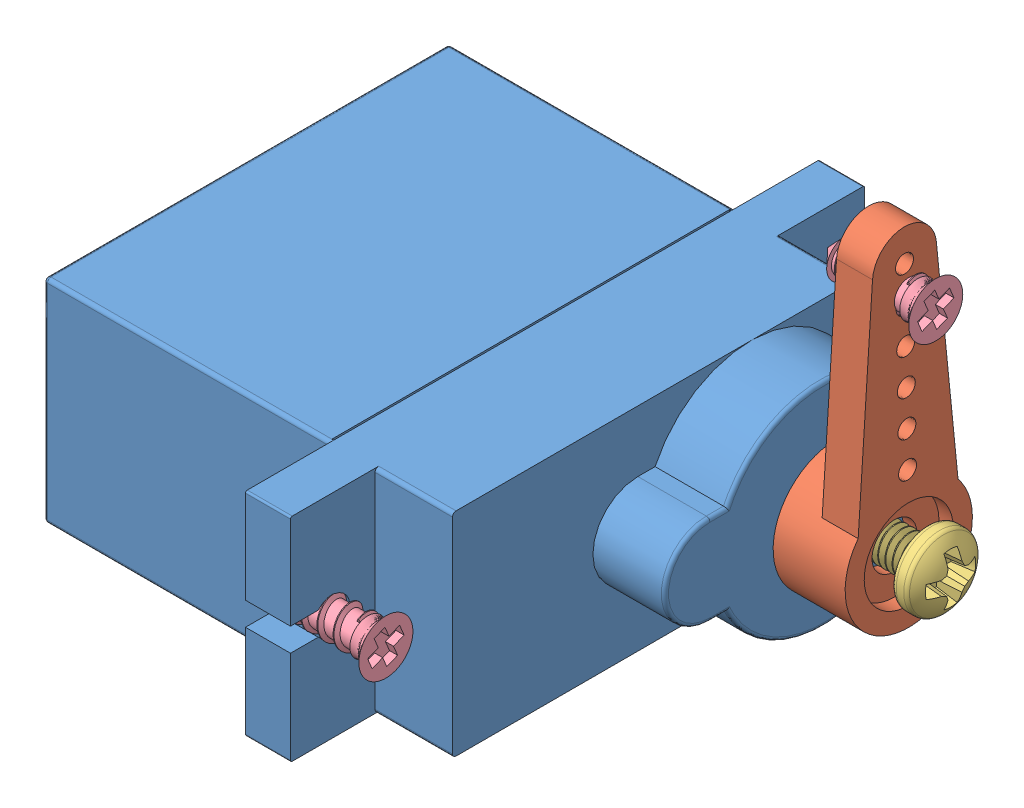
SolidWorks assembly AR2, configuration Predeterminado. Lengths in mm.
Overall size (34.06 21.82 31.9).
6 component instances, 4 part files, 21 mates.
Components (placement in the parent):
- sg90-1: sg90 [Default] at (175.3764 -204.8635 98.9775) x (0 0 1) z (0 1 0) size (31.9 29.9 11.8)
- SG90 plastic Horn-1: SG90 plastic Horn [Default] at (204.8264 -198.9635 104.8775) x (0 0.999858 0.016879) z (0 0.016879 -0.999858) size (19.4 4 7.07)
- (M2_3_mm)_90116A007_METRIC 316 SS PAN HEAD PHILLIPS MACHINE SCREW-1: (M2_3_mm)_90116A007_METRIC 316 SS PAN HEAD PHILLIPS MACHINE SCREW [90116A007] at (204.8264 -198.9635 104.8775) x (0 0 -1) z (1 0 0) size (4 4 4.68)
- M2x6 SelfTap Screw-2: M2x6 SelfTap Screw [Predeterminado] at (208.3264 -186.4635 104.8775) x (0 -0.924225 -0.381849) z (1 0 0) size (3.4 3.28 6)
- M2x6 SelfTap Screw-4: M2x6 SelfTap Screw [Predeterminado] at (196.7764 -198.9635 123.8775) x (0 -0.924225 -0.381849) z (1 0 0) size (3.4 3.28 6)
- M2x6 SelfTap Screw-6: M2x6 SelfTap Screw [Predeterminado] at (196.7764 -198.9635 96.5775) x (0 -0.924225 -0.381849) z (1 0 0) size (3.4 3.28 6)
Mates (geometry in assembly coordinates):
- Coincidente272: coincident: plane of sg90-1 through (205.2764 -198.9635 104.8775) normal (1 0 0); plane of SG90 plastic Horn-1 through (205.2764 -197.7187 104.8985) normal (-1 0 0)
- Concéntrica139: concentric: circle of sg90-1; circle of SG90 plastic Horn-1
- Concéntrica154: concentric: circle of sg90-1; circle of M2x6 SelfTap Screw-6
- Distancia47: distance = 3 mm: plane of M2x6 SelfTap Screw-6 through (196.7764 -198.9635 96.5775) normal (1 0 0); plane of sg90-1 through (193.7764 -204.8635 94.2775) normal (1 0 0)
- Concéntrica155: concentric: circle of sg90-1; circle of M2x6 SelfTap Screw-4
- Distancia48: distance = 3 mm: plane of M2x6 SelfTap Screw-4 through (196.7764 -198.9635 123.8775) normal (1 0 0); plane of sg90-1 through (193.7764 -193.0635 126.1775) normal (1 0 0)
- Coincidente273: coincident: plane of ? through (96.918 -198.9635 104.8775) normal (-1 0 0); plane of ? through (96.918 -197.7188 104.9044) normal (1 0 0)
- Concéntrica140: concentric: circle of ?; circle of ?
- Concéntrica156: concentric: circle of ?; circle of ?
- Distancia49: distance = 1 mm: plane of ? through (107.418 -198.9635 96.5775) normal (-1 0 0); plane of ? through (108.418 -193.0635 94.2775) normal (-1 0 0)
- Concéntrica158: concentric: circle of ?; circle of ?
- Distancia50: distance = 1 mm: plane of ? through (107.418 -198.9635 123.8775) normal (-1 0 0); plane of ? through (108.418 -204.8635 126.1775) normal (-1 0 0)
- Coincidente278: coincident: plane of ? through (95.368 -195.4293 104.9539) normal (-1 0 0); plane of ? through (95.368 -158.9009 108.4991) normal (1 0 0)
- Concéntrica144: concentric: circle of ?; circle of ?
- Bloquear2: lock: unknown of ?; unknown of ?
- Bloquear3: lock: unknown of ?; unknown of ?
- Bloquear4: lock: unknown of ?; unknown of ?
- Coincidente282: coincident: plane of ? through (94.368 -158.9009 108.4991) normal (-1 0 0); plane of ? through (94.368 -198.9635 104.8775) normal (1 0 0)
- Concéntrica146: concentric: circle of ?; circle of ?
- Concéntrica147: concentric: circle of ?; circle of ?
- Distancia45: distance = 0.5 mm: plane of ? through (93.868 -186.4635 104.8775) normal (-1 0 0); plane of ? through (94.368 -158.9009 108.4991) normal (-1 0 0)
